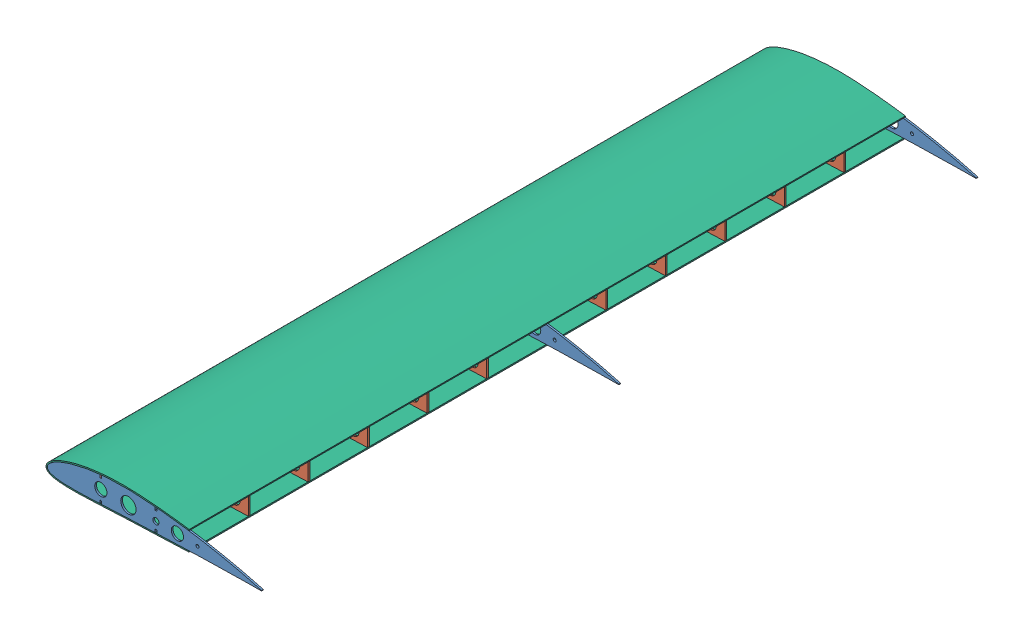
SolidWorks assembly Сборка1, configuration Default. Lengths in mm.
Overall size (357.75 54.9 1178.91).
27 component instances, 6 part files, 79 mates.
Components (placement in the parent):
- polywoodRib350mm-1: polywoodRib350mm [Default] at (-125.2616 109.5433 380.1754) size (350.22 44.96 2.8)
- polywoodAileronRib350mm-1: polywoodAileronRib350mm [Default] at (-125.2616 109.5433 282.9754) size (350.04 44.96 2.8)
- polywoodStringer-1: polywoodStringer [Default] at (-37.7616 138.4489 282.9754) x (0 0 -1) z (1 0 0) size (102.8 7.84 2.8)
- polywoodAileronRib350mm-3: polywoodAileronRib350mm [Default] at (-125.2616 109.5433 185.7754) size (350.04 44.96 2.8)
- polywoodAileronRib350mm-4: polywoodAileronRib350mm [Default] at (-125.2616 109.5433 88.5754) size (350.04 44.96 2.8)
- polywoodStringer-2: polywoodStringer [Default] at (-37.7616 138.4489 185.7754) x (0 0 -1) z (1 0 0) size (102.8 7.84 2.8)
- polywoodAileronRib350mm-5: polywoodAileronRib350mm [Default] at (-125.2616 109.5433 -8.6246) size (350.04 44.96 2.8)
- polywoodAileronRib350mm-6: polywoodAileronRib350mm [Default] at (-125.2616 109.5433 -105.8246) size (350.04 44.96 2.8)
- polywoodAileronRib350mm-8: polywoodAileronRib350mm [Default] at (-125.2616 109.5433 -300.2246) size (350.04 44.96 2.8)
- polywoodAileronRib350mm-9: polywoodAileronRib350mm [Default] at (-125.2616 109.5433 -397.4246) size (350.04 44.96 2.8)
- polywoodAileronRib350mm-10: polywoodAileronRib350mm [Default] at (-125.2616 109.5433 -494.6246) size (350.04 44.96 2.8)
- polywoodAileronRib350mm-11: polywoodAileronRib350mm [Default] at (-125.2616 109.5433 -689.0246) size (350.04 44.96 2.8)
- polywoodAileronRib350mm-12: polywoodAileronRib350mm [Default] at (-125.2616 109.5433 -591.8246) size (350.04 44.96 2.8)
- polywoodRib350mm-4: polywoodRib350mm [Default] at (-125.2616 109.5433 -786.2246) size (350.22 44.96 2.8)
- polywoodRib350mm-5: polywoodRib350mm [Default] at (-125.2616 109.5433 -203.0246) size (350.22 44.96 2.8)
- polywoodStringer-3: polywoodStringer [Default] at (-37.7616 138.4489 88.5754) x (0 0 -1) z (1 0 0) size (102.8 7.84 2.8)
- polywoodStringer-4: polywoodStringer [Default] at (-37.7616 138.4489 -8.6246) x (0 0 -1) z (1 0 0) size (102.8 7.84 2.8)
- polywoodStringer-5: polywoodStringer [Default] at (-37.7616 138.4489 -105.8246) x (0 0 -1) z (1 0 0) size (102.8 7.84 2.8)
- polywoodStringer-6: polywoodStringer [Default] at (-37.7616 138.4489 -203.0246) x (0 0 -1) z (1 0 0) size (102.8 7.84 2.8)
- polywoodStringer-7: polywoodStringer [Default] at (-37.7616 138.4489 -300.2246) x (0 0 -1) z (1 0 0) size (102.8 7.84 2.8)
- polywoodStringer-8: polywoodStringer [Default] at (-37.7616 138.4489 -397.4246) x (0 0 -1) z (1 0 0) size (102.8 7.84 2.8)
- polywoodStringer-9: polywoodStringer [Default] at (-37.7616 138.4489 -494.6246) x (0 0 -1) z (1 0 0) size (102.8 7.84 2.8)
- polywoodStringer-10: polywoodStringer [Default] at (-37.7616 138.4489 -591.8246) x (0 0 -1) z (1 0 0) size (102.8 7.84 2.8)
- polywoodStringer-11: polywoodStringer [Default] at (-37.7616 138.4489 -689.0246) x (0 0 -1) z (1 0 0) size (102.8 7.84 2.8)
- PolywoodSparRoot-1: PolywoodSparRoot [Default] at (-37.7616 139.5689 347.6325) x (0 0 -1) z (-1 0 0) size (52.8 7.84 2.8)
- PolywoodSparRoot1-1: PolywoodSparRoot1 [Default] at (-37.7616 138.4489 -761.2246) x (0 0 -1) z (1 0 0) size (52.8 7.84 2.8)
- WingEnclosureXPS-1: WingEnclosureXPS [Default] at origin size (244.91 54.9 1178.91)
Mates (geometry in assembly coordinates):
- Концентричный1: concentric aligned: cylinder of polywoodRib350mm-1 through (-37.7616 121.5746 381.5754) axis (0 0 -1) radius 10; cylinder of polywoodAileronRib350mm-1 through (-37.7616 121.5746 284.3754) axis (0 0 -1) radius 10
- Концентричный2: concentric aligned: cylinder of polywoodRib350mm-1 through (52.2384 121.5746 381.5754) axis (0 0 -1) radius 5; cylinder of polywoodAileronRib350mm-1 through (52.2384 121.5746 284.3754) axis (0 0 -1) radius 5
- Концентричный5: concentric aligned: cylinder of polywoodAileronRib350mm-1 through (-37.7616 121.5746 284.3754) axis (0 0 -1) radius 10; cylinder of polywoodAileronRib350mm-3 through (-37.7616 121.5746 187.1754) axis (0 0 -1) radius 10
- Концентричный6: concentric aligned: cylinder of polywoodAileronRib350mm-1 through (52.2384 121.5746 284.3754) axis (0 0 -1) radius 5; cylinder of polywoodAileronRib350mm-3 through (52.2384 121.5746 187.1754) axis (0 0 -1) radius 5
- Концентричный7: concentric aligned: cylinder of polywoodAileronRib350mm-3 through (52.2384 121.5746 187.1754) axis (0 0 -1) radius 5; cylinder of polywoodAileronRib350mm-4 through (52.2384 121.5746 89.9754) axis (0 0 -1) radius 5
- Концентричный8: concentric aligned: cylinder of polywoodAileronRib350mm-3 through (-37.7616 121.5746 187.1754) axis (0 0 -1) radius 10; cylinder of polywoodAileronRib350mm-4 through (-37.7616 121.5746 89.9754) axis (0 0 -1) radius 10
- Совпадение5: coincident anti-aligned: plane of polywoodAileronRib350mm-1 through (-85.5642 133.4877 284.3754) normal (0 0 1); plane of polywoodStringer-1 through (-36.3616 134.5289 284.3754) normal (0 0 -1)
- Совпадение6: coincident anti-aligned: plane of polywoodAileronRib350mm-1 through (-36.3616 142.5063 284.3754) normal (-1 0 0); plane of polywoodStringer-1 through (-36.3616 138.4489 282.9754) normal (1 0 0)
- Совпадение7: coincident anti-aligned: plane of polywoodAileronRib350mm-1 through (-39.1616 137.3289 284.3754) normal (0 1 0); plane of polywoodStringer-1 through (-36.3616 137.3289 284.3754) normal (0 -1 0)
- Совпадение10: coincident anti-aligned: plane of polywoodAileronRib350mm-3 through (-85.5642 133.4877 184.3754) normal (0 0 -1); plane of polywoodStringer-2 through (-36.3616 134.5289 184.3754) normal (0 0 1)
- Совпадение11: coincident anti-aligned: plane of polywoodAileronRib350mm-3 through (-36.3616 142.5063 187.1754) normal (-1 0 0); plane of polywoodStringer-2 through (-36.3616 138.4489 185.7754) normal (1 0 0)
- Совпадение12: coincident anti-aligned: plane of polywoodAileronRib350mm-3 through (-39.1616 137.3289 187.1754) normal (0 1 0); plane of polywoodStringer-2 through (-36.3616 137.3289 187.1754) normal (0 -1 0)
- Совпадение15: coincident anti-aligned: plane of polywoodStringer-1 through (-36.3616 142.3689 237.1754) normal (0 0 -1); plane of polywoodStringer-2 through (-36.3616 138.4489 237.1754) normal (0 0 1)
- Расстояние3: distance = 100 mm anti-aligned: plane of polywoodAileronRib350mm-3 through (-85.5642 133.4877 187.1754) normal (0 0 1); plane of polywoodAileronRib350mm-4 through (-85.5642 133.4877 87.1754) normal (0 0 -1)
- Концентричный9: concentric aligned: cylinder of polywoodAileronRib350mm-4 through (-37.7616 121.5746 89.9754) axis (0 0 -1) radius 10; cylinder of polywoodAileronRib350mm-5 through (-37.7616 121.5746 -7.2246) axis (0 0 -1) radius 10
- Концентричный10: concentric aligned: cylinder of polywoodAileronRib350mm-4 through (52.2384 121.5746 89.9754) axis (0 0 -1) radius 5; cylinder of polywoodAileronRib350mm-5 through (52.2384 121.5746 -7.2246) axis (0 0 -1) radius 5
- Расстояние4: distance = 100 mm anti-aligned: plane of polywoodAileronRib350mm-4 through (-85.5642 133.4877 89.9754) normal (0 0 1); plane of polywoodAileronRib350mm-5 through (-85.5642 133.4877 -10.0246) normal (0 0 -1)
- Концентричный11: concentric aligned: cylinder of polywoodAileronRib350mm-5 through (52.2384 121.5746 -7.2246) axis (0 0 -1) radius 5; cylinder of polywoodAileronRib350mm-6 through (52.2384 121.5746 -104.4246) axis (0 0 -1) radius 5
- Расстояние5: distance = 100 mm anti-aligned: plane of polywoodAileronRib350mm-6 through (-85.5642 133.4877 -107.2246) normal (0 0 -1); plane of polywoodAileronRib350mm-5 through (-85.5642 133.4877 -7.2246) normal (0 0 1)
- Концентричный12: concentric aligned: cylinder of polywoodAileronRib350mm-5 through (-37.7616 121.5746 -7.2246) axis (0 0 -1) radius 10; cylinder of polywoodAileronRib350mm-6 through (-37.7616 121.5746 -104.4246) axis (0 0 -1) radius 10
- Концентричный17: concentric aligned: cylinder of polywoodAileronRib350mm-8 through (-37.7616 121.5746 -298.8246) axis (0 0 -1) radius 10; cylinder of polywoodAileronRib350mm-9 through (-37.7616 121.5746 -396.0246) axis (0 0 -1) radius 10
- Концентричный18: concentric aligned: cylinder of polywoodAileronRib350mm-8 through (52.2384 121.5746 -298.8246) axis (0 0 -1) radius 5; cylinder of polywoodAileronRib350mm-9 through (52.2384 121.5746 -396.0246) axis (0 0 -1) radius 5
- Расстояние8: distance = 100 mm anti-aligned: plane of polywoodAileronRib350mm-8 through (-85.5642 133.4877 -298.8246) normal (0 0 1); plane of polywoodAileronRib350mm-9 through (-85.5642 133.4877 -398.8246) normal (0 0 -1)
- Концентричный19: concentric aligned: cylinder of polywoodAileronRib350mm-9 through (-37.7616 121.5746 -396.0246) axis (0 0 -1) radius 10; cylinder of polywoodAileronRib350mm-10 through (-37.7616 121.5746 -493.2246) axis (0 0 -1) radius 10
- Концентричный20: concentric aligned: cylinder of polywoodAileronRib350mm-9 through (52.2384 121.5746 -396.0246) axis (0 0 -1) radius 5; cylinder of polywoodAileronRib350mm-10 through (52.2384 121.5746 -493.2246) axis (0 0 -1) radius 5
- Расстояние9: distance = 100 mm anti-aligned: plane of polywoodAileronRib350mm-9 through (-85.5642 133.4877 -396.0246) normal (0 0 1); plane of polywoodAileronRib350mm-10 through (-85.5642 133.4877 -496.0246) normal (0 0 -1)
- Концентричный21: concentric aligned: cylinder of polywoodAileronRib350mm-10 through (-37.7616 121.5746 -493.2246) axis (0 0 -1) radius 10; cylinder of polywoodAileronRib350mm-12 through (-37.7616 121.5746 -590.4246) axis (0 0 -1) radius 10
- Расстояние10: distance = 100 mm anti-aligned: plane of polywoodAileronRib350mm-10 through (-85.5642 133.4877 -493.2246) normal (0 0 1); plane of polywoodAileronRib350mm-12 through (-85.5642 133.4877 -593.2246) normal (0 0 -1)
- Концентричный22: concentric aligned: cylinder of polywoodAileronRib350mm-10 through (52.2384 121.5746 -493.2246) axis (0 0 -1) radius 5; cylinder of polywoodAileronRib350mm-12 through (52.2384 121.5746 -590.4246) axis (0 0 -1) radius 5
- Концентричный23: concentric aligned: cylinder of polywoodAileronRib350mm-11 through (-37.7616 121.5746 -687.6246) axis (0 0 -1) radius 10; cylinder of polywoodAileronRib350mm-12 through (-37.7616 121.5746 -590.4246) axis (0 0 -1) radius 10
- Концентричный24: concentric aligned: cylinder of polywoodAileronRib350mm-11 through (52.2384 121.5746 -687.6246) axis (0 0 -1) radius 5; cylinder of polywoodAileronRib350mm-12 through (52.2384 121.5746 -590.4246) axis (0 0 -1) radius 5
- Расстояние11: distance = 100 mm anti-aligned: plane of polywoodAileronRib350mm-12 through (-85.5642 133.4877 -590.4246) normal (0 0 1); plane of polywoodAileronRib350mm-11 through (-85.5642 133.4877 -690.4246) normal (0 0 -1)
- Концентричный25: concentric aligned: cylinder of polywoodRib350mm-1 through (-37.7616 121.5746 381.5754) axis (0 0 -1) radius 10; cylinder of polywoodRib350mm-4 through (-37.7616 121.5746 -784.8246) axis (0 0 -1) radius 10
- Концентричный26: concentric aligned: cylinder of polywoodRib350mm-1 through (52.2384 121.5746 381.5754) axis (0 0 -1) radius 5; cylinder of polywoodRib350mm-4 through (52.2384 121.5746 -784.8246) axis (0 0 -1) radius 5
- Концентричный27: concentric aligned: cylinder of polywoodAileronRib350mm-6 through (-37.7616 121.5746 -104.4246) axis (0 0 -1) radius 10; cylinder of polywoodRib350mm-5 through (-37.7616 121.5746 -201.6246) axis (0 0 -1) radius 10
- Концентричный28: concentric aligned: cylinder of polywoodAileronRib350mm-6 through (52.2384 121.5746 -104.4246) axis (0 0 -1) radius 5; cylinder of polywoodRib350mm-5 through (52.2384 121.5746 -201.6246) axis (0 0 -1) radius 5
- Расстояние13: distance = 100 mm anti-aligned: plane of polywoodAileronRib350mm-6 through (-85.5642 133.4877 -104.4246) normal (0 0 1); plane of polywoodRib350mm-5 through (-85.5642 133.4877 -204.4246) normal (0 0 -1)
- Концентричный29: concentric aligned: cylinder of polywoodAileronRib350mm-8 through (-37.7616 121.5746 -298.8246) axis (0 0 -1) radius 10; cylinder of polywoodRib350mm-5 through (-37.7616 121.5746 -201.6246) axis (0 0 -1) radius 10
- Концентричный30: concentric aligned: cylinder of polywoodAileronRib350mm-8 through (52.2384 121.5746 -298.8246) axis (0 0 -1) radius 5; cylinder of polywoodRib350mm-5 through (52.2384 121.5746 -201.6246) axis (0 0 -1) radius 5
- Расстояние14: distance = 100 mm anti-aligned: plane of polywoodRib350mm-5 through (-85.5642 133.4877 -201.6246) normal (0 0 1); plane of polywoodAileronRib350mm-8 through (-85.5642 133.4877 -301.6246) normal (0 0 -1)
- Расстояние16: distance = 100 mm anti-aligned: plane of polywoodRib350mm-1 through (-85.5642 133.4877 381.5754) normal (0 0 1); plane of polywoodAileronRib350mm-1 through (-85.5642 133.4877 281.5754) normal (0 0 -1)
- Расстояние17: distance = 100 mm anti-aligned: plane of polywoodAileronRib350mm-11 through (-85.5642 133.4877 -687.6246) normal (0 0 1); plane of polywoodRib350mm-4 through (-85.5642 133.4877 -787.6246) normal (0 0 -1)
- Совпадение31: coincident anti-aligned: plane of polywoodAileronRib350mm-4 through (-36.3616 142.5063 89.9754) normal (-1 0 0); plane of polywoodStringer-3 through (-36.3616 138.4489 88.5754) normal (1 0 0)
- Совпадение32: coincident anti-aligned: plane of polywoodAileronRib350mm-4 through (-85.5642 133.4877 87.1754) normal (0 0 -1); plane of polywoodStringer-3 through (-36.3616 134.5289 87.1754) normal (0 0 1)
- Совпадение33: coincident anti-aligned: plane of polywoodAileronRib350mm-4 through (-39.1616 137.3289 89.9754) normal (0 1 0); plane of polywoodStringer-3 through (-36.3616 137.3289 89.9754) normal (0 -1 0)
- Совпадение34: coincident aligned: plane of polywoodStringer-3 through (-36.3616 138.4489 88.5754) normal (1 0 0); plane of polywoodStringer-4 through (-36.3616 138.4489 -8.6246) normal (1 0 0)
- Совпадение35: coincident anti-aligned: plane of polywoodStringer-3 through (-36.3616 134.5289 37.1754) normal (0 0 -1); plane of polywoodStringer-4 through (-36.3616 138.4489 37.1754) normal (0 0 1)
- Совпадение36: coincident anti-aligned: plane of polywoodStringer-3 through (-36.3616 138.4489 42.7754) normal (0 1 0); plane of polywoodStringer-4 through (-36.3616 138.4489 42.7754) normal (0 -1 0)
- Совпадение37: coincident aligned: plane of polywoodStringer-4 through (-36.3616 138.4489 -8.6246) normal (1 0 0); plane of polywoodStringer-5 through (-36.3616 138.4489 -105.8246) normal (1 0 0)
- Совпадение38: coincident anti-aligned: plane of polywoodStringer-4 through (-36.3616 138.4489 -54.4246) normal (0 1 0); plane of polywoodStringer-5 through (-36.3616 138.4489 -54.4246) normal (0 -1 0)
- Совпадение39: coincident anti-aligned: plane of polywoodStringer-4 through (-36.3616 142.3689 -54.4246) normal (0 0 -1); plane of polywoodStringer-5 through (-36.3616 138.4489 -54.4246) normal (0 0 1)
- Совпадение40: coincident anti-aligned: plane of polywoodStringer-5 through (-36.3616 134.5289 -157.2246) normal (0 0 -1); plane of polywoodStringer-6 through (-36.3616 138.4489 -157.2246) normal (0 0 1)
- Совпадение41: coincident aligned: plane of polywoodStringer-5 through (-36.3616 138.4489 -105.8246) normal (1 0 0); plane of polywoodStringer-6 through (-36.3616 138.4489 -203.0246) normal (1 0 0)
- Совпадение42: coincident anti-aligned: plane of polywoodStringer-5 through (-36.3616 138.4489 -151.6246) normal (0 1 0); plane of polywoodStringer-6 through (-36.3616 138.4489 -151.6246) normal (0 -1 0)
- Совпадение43: coincident anti-aligned: plane of polywoodAileronRib350mm-8 through (-85.5642 133.4877 -301.6246) normal (0 0 -1); plane of polywoodStringer-7 through (-36.3616 134.5289 -301.6246) normal (0 0 1)
- Совпадение44: coincident aligned: plane of polywoodStringer-6 through (-36.3616 138.4489 -203.0246) normal (1 0 0); plane of polywoodStringer-7 through (-36.3616 138.4489 -300.2246) normal (1 0 0)
- Совпадение45: coincident anti-aligned: plane of polywoodStringer-6 through (-36.3616 138.4489 -248.8246) normal (0 1 0); plane of polywoodStringer-7 through (-36.3616 138.4489 -248.8246) normal (0 -1 0)
- Совпадение46: coincident anti-aligned: plane of polywoodAileronRib350mm-9 through (-85.5642 133.4877 -398.8246) normal (0 0 -1); plane of polywoodStringer-8 through (-36.3616 134.5289 -398.8246) normal (0 0 1)
- Совпадение47: coincident aligned: plane of polywoodStringer-7 through (-36.3616 138.4489 -300.2246) normal (1 0 0); plane of polywoodStringer-8 through (-36.3616 138.4489 -397.4246) normal (1 0 0)
- Совпадение48: coincident anti-aligned: plane of polywoodStringer-7 through (-36.3616 138.4489 -346.0246) normal (0 1 0); plane of polywoodStringer-8 through (-36.3616 138.4489 -346.0246) normal (0 -1 0)
- Совпадение49: coincident aligned: plane of polywoodStringer-8 through (-36.3616 138.4489 -397.4246) normal (1 0 0); plane of polywoodStringer-9 through (-36.3616 138.4489 -494.6246) normal (1 0 0)
- Совпадение50: coincident anti-aligned: plane of polywoodStringer-8 through (-36.3616 134.5289 -448.8246) normal (0 0 -1); plane of polywoodStringer-9 through (-36.3616 138.4489 -448.8246) normal (0 0 1)
- Совпадение51: coincident anti-aligned: plane of polywoodStringer-8 through (-36.3616 138.4489 -443.2246) normal (0 1 0); plane of polywoodStringer-9 through (-36.3616 138.4489 -443.2246) normal (0 -1 0)
- Совпадение52: coincident aligned: plane of polywoodStringer-9 through (-36.3616 138.4489 -494.6246) normal (1 0 0); plane of polywoodStringer-10 through (-36.3616 138.4489 -591.8246) normal (1 0 0)
- Совпадение53: coincident anti-aligned: plane of polywoodStringer-9 through (-36.3616 138.4489 -540.4246) normal (0 1 0); plane of polywoodStringer-10 through (-36.3616 138.4489 -540.4246) normal (0 -1 0)
- Совпадение54: coincident anti-aligned: plane of polywoodStringer-9 through (-36.3616 142.3689 -540.4246) normal (0 0 -1); plane of polywoodStringer-10 through (-36.3616 138.4489 -540.4246) normal (0 0 1)
- Совпадение55: coincident aligned: plane of polywoodStringer-10 through (-36.3616 138.4489 -591.8246) normal (1 0 0); plane of polywoodStringer-11 through (-36.3616 138.4489 -689.0246) normal (1 0 0)
- Совпадение56: coincident anti-aligned: plane of polywoodStringer-10 through (-36.3616 138.4489 -637.6246) normal (0 1 0); plane of polywoodStringer-11 through (-36.3616 138.4489 -637.6246) normal (0 -1 0)
- Совпадение57: coincident anti-aligned: plane of polywoodStringer-10 through (-36.3616 142.3689 -637.6246) normal (0 0 -1); plane of polywoodStringer-11 through (-36.3616 138.4489 -637.6246) normal (0 0 1)
- Совпадение63: coincident aligned: plane of polywoodStringer-1 through (-36.3616 138.4489 282.9754) normal (1 0 0); plane of PolywoodSparRoot-1 through (-36.3616 139.5689 347.6325) normal (1 0 0)
- Совпадение64: coincident aligned: plane of polywoodRib350mm-1 through (-85.5642 133.4877 381.5754) normal (0 0 1); plane of PolywoodSparRoot-1 through (-39.1616 139.5689 381.5754) normal (0 0 1)
- Совпадение65: coincident anti-aligned: plane of polywoodStringer-1 through (-36.3616 138.4489 334.3754) normal (0 -1 0); plane of PolywoodSparRoot-1 through (-39.1616 138.4489 328.7754) normal (0 1 0)
- Совпадение71: coincident anti-aligned: plane of polywoodStringer-11 through (-36.3616 142.3689 -734.8246) normal (0 0 -1); plane of Деталь3^Сборка1-1 through (-36.3616 138.4489 -734.8246) normal (0 0 1)
- Совпадение72: coincident aligned: plane of polywoodStringer-11 through (-36.3616 138.4489 -689.0246) normal (1 0 0); plane of Деталь3^Сборка1-1 through (-36.3616 138.4489 -761.2246) normal (1 0 0)
- Совпадение73: coincident anti-aligned: plane of polywoodStringer-11 through (-36.3616 138.4489 -734.8246) normal (0 1 0); plane of Деталь3^Сборка1-1 through (-36.3616 138.4489 -734.8246) normal (0 -1 0)
- На месте3: in place: plane of WingEnclosureXPS-1 through (0 0 0) normal (0 0 1); moOrthogonalPlaneRef_w of WingEnclosureXPS-1 through (0 0 0) normal (0 1 0); plane of WingEnclosureXPS-1 through (0 0 0) normal (1 0 0); unknown of WingEnclosureXPS-1
- Совпадение95: coincident aligned: 
- Совпадение96: coincident aligned: plane of Деталь4^Сборка1-1 through (0 0 0) normal (0 1 0)
- Совпадение97: coincident anti-aligned: plane of Деталь4^Сборка1-1 through (0 0 0) normal (1 0 0)
